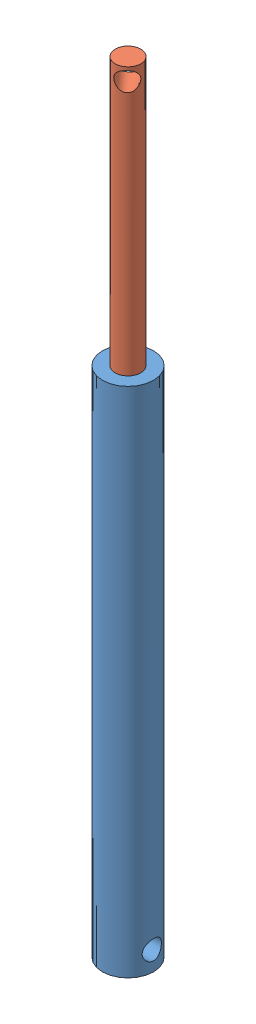
SolidWorks assembly hcl, configuration Default. Lengths in mm.
Overall size (40 608.97 40).
2 component instances, 2 part files, 1 mates.
Components (placement in the parent):
- hcl1-1: hcl1 [Default] at origin size (40 400 40)
- hcl2-1: hcl2 [Default] at (0 608.9732 0) x (0.664107 0 0.747637) z (0 -1 0) size (20 20 500)
Mates (geometry in assembly coordinates):
- Concentric1: concentric anti-aligned: cylinder of hcl1-1 through (0 400 0) axis (0 -1 0) radius 20; cylinder of hcl2-1 through (0 108.9732 0) axis (0 1 0) radius 10
